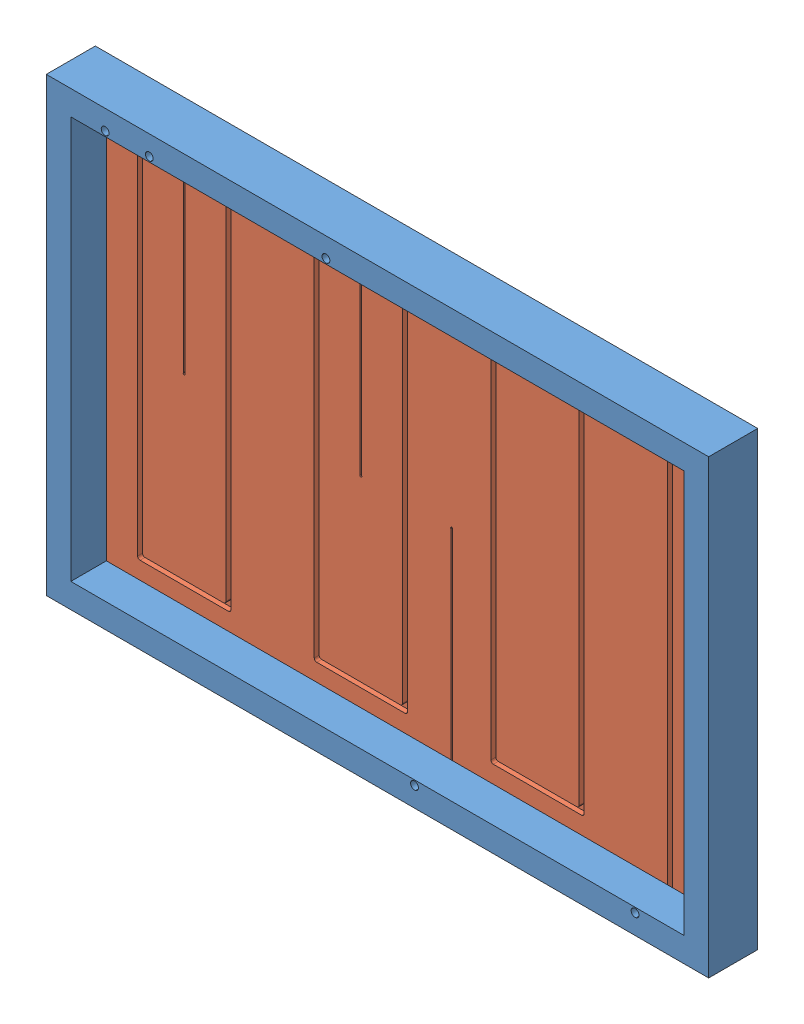
SolidWorks assembly Сборка2, configuration По умолчанию. Lengths in mm.
Overall size (135 92 10).
2 component instances, 2 part files, 0 mates.
Components (placement in the parent):
- Деталь1-1: Деталь1 [По умолчанию] at origin size (135 92 10)
- Крышка-3: Крышка [По умолчанию] at (-0.1518 81.9216 2.7345) x (1 0 0) z (0 1 0) size (129 2.73 86)
